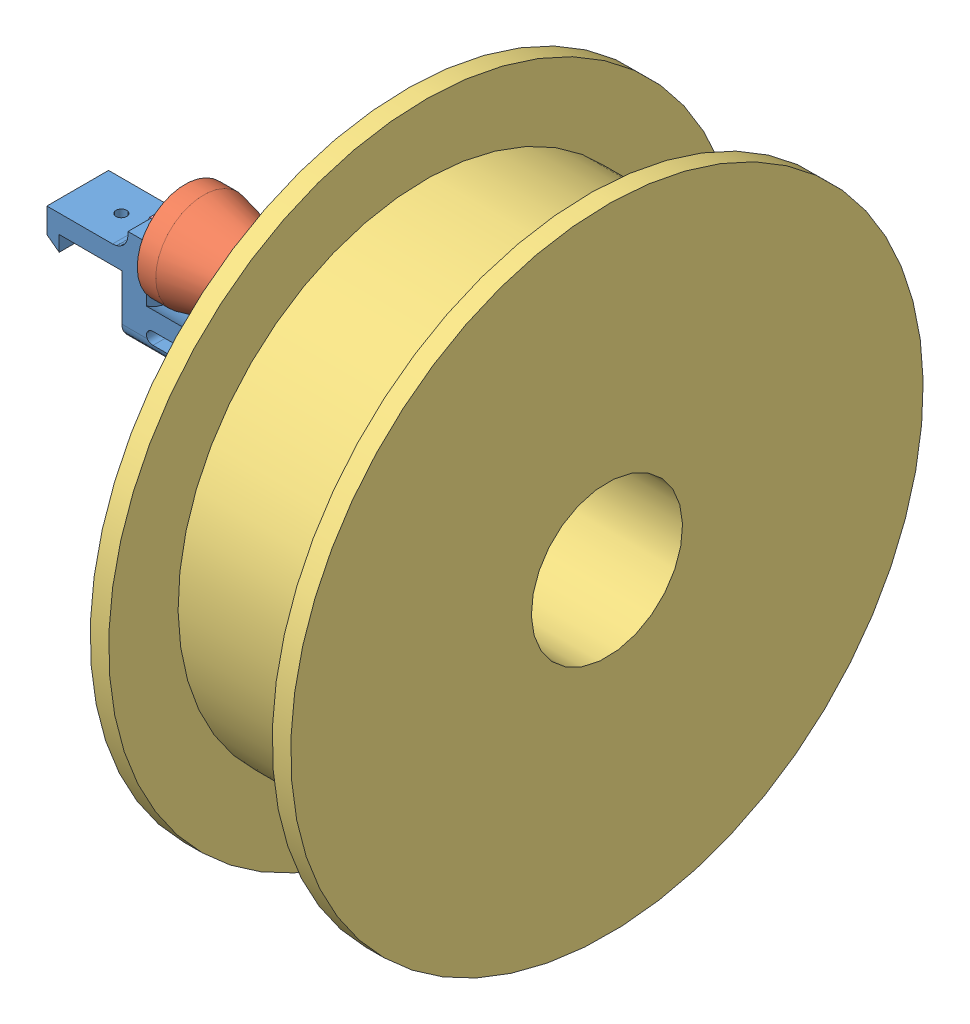
SolidWorks assembly spool holder, configuration Valor predeterminado. Lengths in mm.
Overall size (207.32 274.31 274.31).
4 component instances, 4 part files, 6 mates.
Components (placement in the parent):
- spool holder-1: spool holder [Valor predeterminado] at (-63.6829 9.0139 114) size (143.3 32 20)
- bearing holder-1: bearing holder [Valor predeterminado] at (-28.8829 20.0139 114) x (0 -0.93781 0.347149) z (0 0.347149 0.93781) size (31 100 31)
- filament spool-1: filament spool [Valor predeterminado] at (78.6389 31.411 149.7962) x (0 0.897902 -0.440196) z (0 -0.440196 -0.897902) size (205 65 205)
- axe-1: axe [Valor predeterminado] at (80.1171 20.0139 114) x (0 0 1) z (-1 0 0) size (7.8 6 118)
Mates (geometry in assembly coordinates):
- Concêntrico1: concentric aligned: cylinder of spool holder-1 through (-35.8829 20.0139 114) axis (-1 0 0) radius 15; cylinder of bearing holder-1 through (-28.8829 20.0139 114) axis (-1 0 0) radius 11
- Largura1: width aligned: plane of bearing holder-1 through (71.1171 5.4779 119.3808) normal (1 0 0); plane of bearing holder-1 through (-28.8829 5.4779 119.3808) normal (-1 0 0); plane of spool holder-1 through (73.6171 23.0139 124) normal (-1 0 0); plane of spool holder-1 through (-31.3829 9.0139 124) normal (1 0 0)
- Paralelo1: parallel anti-aligned: cylinder of bearing holder-1 through (-28.8829 20.0139 114) axis (-1 0 0) radius 11; cylinder of filament spool-1 through (108.6282 31.411 149.7962) axis (1 0 0) radius 24.5
- Largura2: width anti-aligned: plane of axe-1 through (-37.8829 20.0139 114) normal (-1 0 0); plane of axe-1 through (80.1171 20.0139 114) normal (1 0 0); plane of spool holder-1 through (-35.8829 16.0139 114) normal (1 0 0); plane of spool holder-1 through (78.1171 20.0139 114) normal (-1 0 0)
- Concêntrico2: concentric anti-aligned: cylinder of spool holder-1 through (-35.8829 20.0139 114) axis (-1 0 0) radius 4; cylinder of axe-1 through (-37.8829 20.0139 114) axis (1 0 0) radius 3.9
- Coincidente1: coincident aligned: plane of spool holder-1 through (-31.3829 23.0139 124) normal (0 1 0); plane of axe-1 through (-37.8829 23.0139 111.508) normal (0 1 0)
